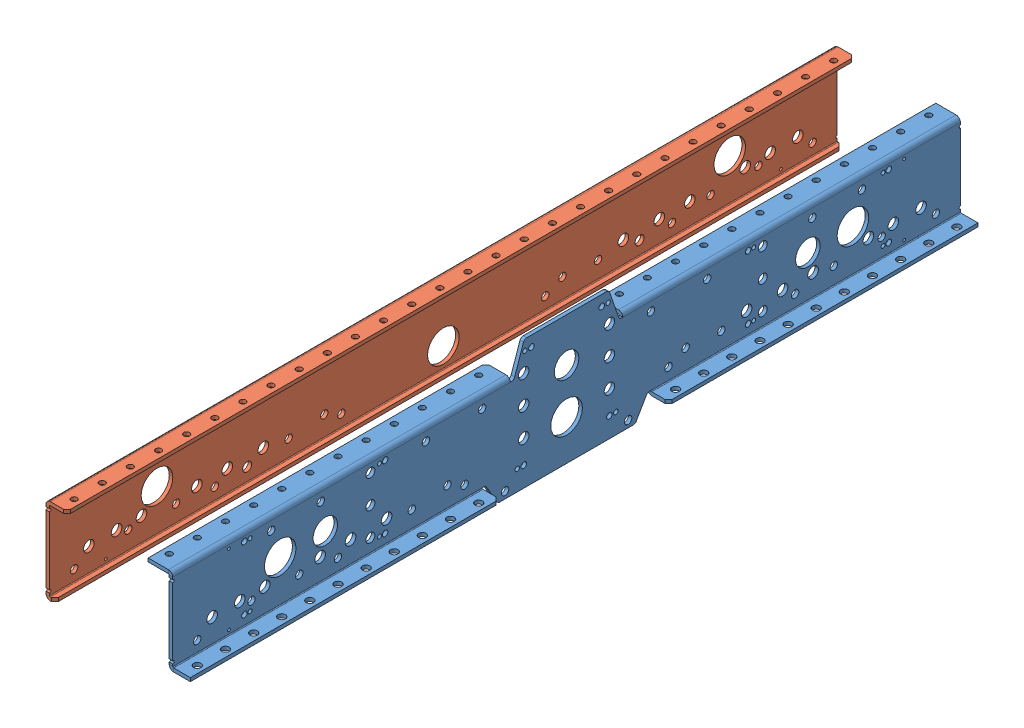
SolidWorks assembly AM14U3Square_Half, configuration Default. Lengths in mm.
Overall size (130.17 116.33 711.33).
3 component instances, 2 part files, 0 mates.
Components (placement in the parent):
- AM14U3Square_Frame_Half-1: AM14U3Square_Frame_Half [Default] at (326.068 37.2757 -291.2758) size (130.18 116.33 711.33)
  - AM14U3InnerPlate_Square-1: AM14U3InnerPlate_Square [Default] at (-733.5226 -76.962 765.048) x (0 0 -1) z (0 -1 0) size (711.2 38.1 116.33)
  - AM14U3OuterPlate_Square-1: AM14U3OuterPlate_Square [Default] at (-820.246 -26.7681 74.8245) x (0 0 1) z (0 -1 0) size (711.2 19.05 77.72)
